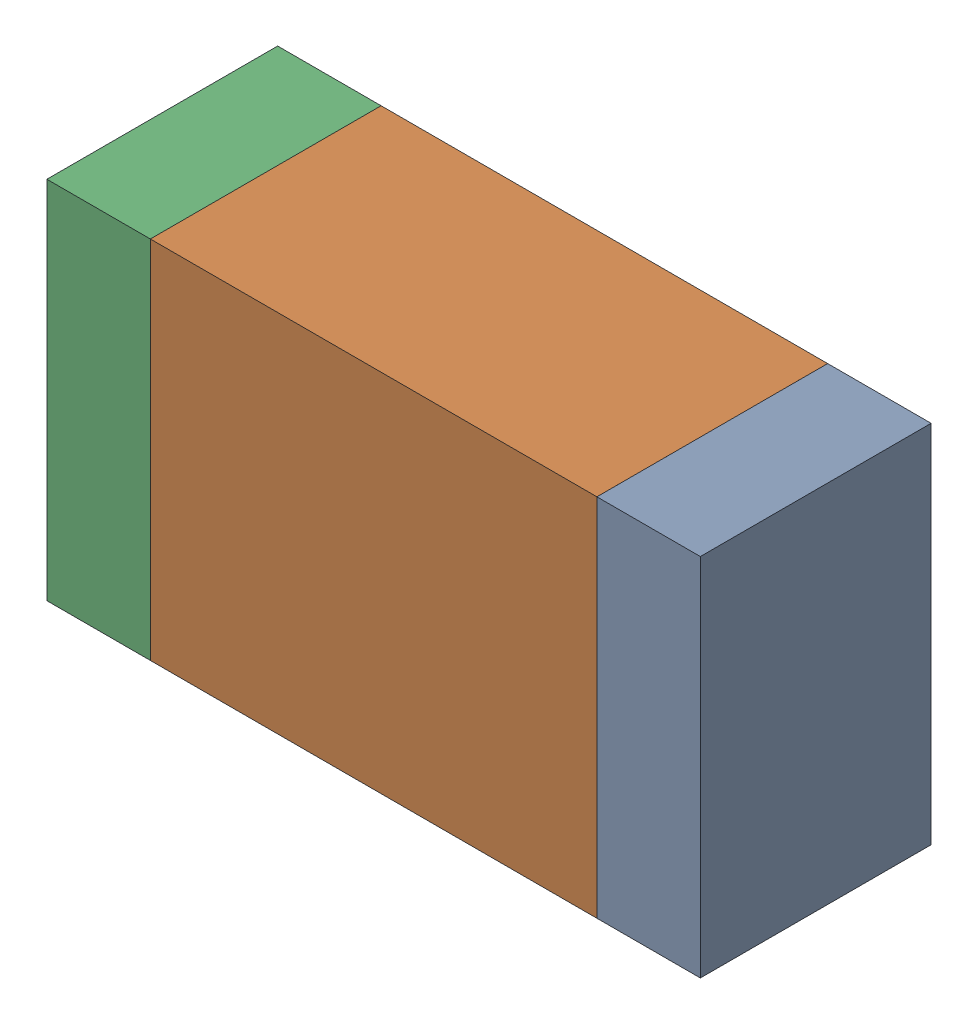
SolidWorks assembly R4-1, configuration Default. Lengths in mm.
Overall size (1.7 0.95 0.6).
6 component instances, 2 part files, 0 mates.
Components (placement in the parent):
- 959209072-1-1: 959209072-1 [Default] at (119.5871 82.2961 0) size (0.27 0.95 0.6)
  - Extruded-52-1: Extruded-52 [Default] at origin size (0.27 0.95 0.6)
- 959209208-1-1: 959209208-1 [Default] at (118.8721 82.2961 0) size (1.16 0.95 0.6)
  - Extruded-53-1: Extruded-53 [Default] at origin size (1.16 0.95 0.6)
- 959209072-1-2: 959209072-1 [Default] at (118.1571 82.2961 0) size (0.27 0.95 0.6)
  - Extruded-52-1: Extruded-52 [Default] at origin size (0.27 0.95 0.6)
